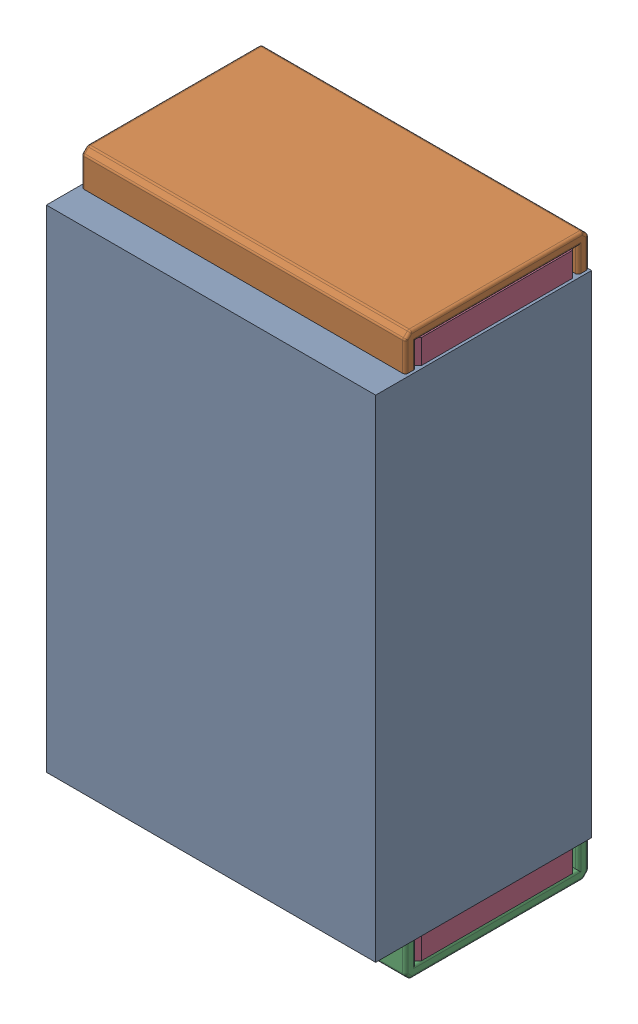
SolidWorks assembly R4, configuration Default. Lengths in mm.
Overall size (0.61 1.04 0.4).
3 component instances, 2 part files, 0 mates.
Components (placement in the parent):
- 1088881848-1: 1088881848 [Default] at (5.975 41.6 0) size (0.61 0.91 0.4)
  - Extruded-1-1: Extruded-1 [Default] at origin size (0.61 0.91 0.4)
- R0402-1: R0402 [Default] at (5.975 41.6 0) x (0 1 0) z (1 0 0) size (1.04 0.34 0.6)
